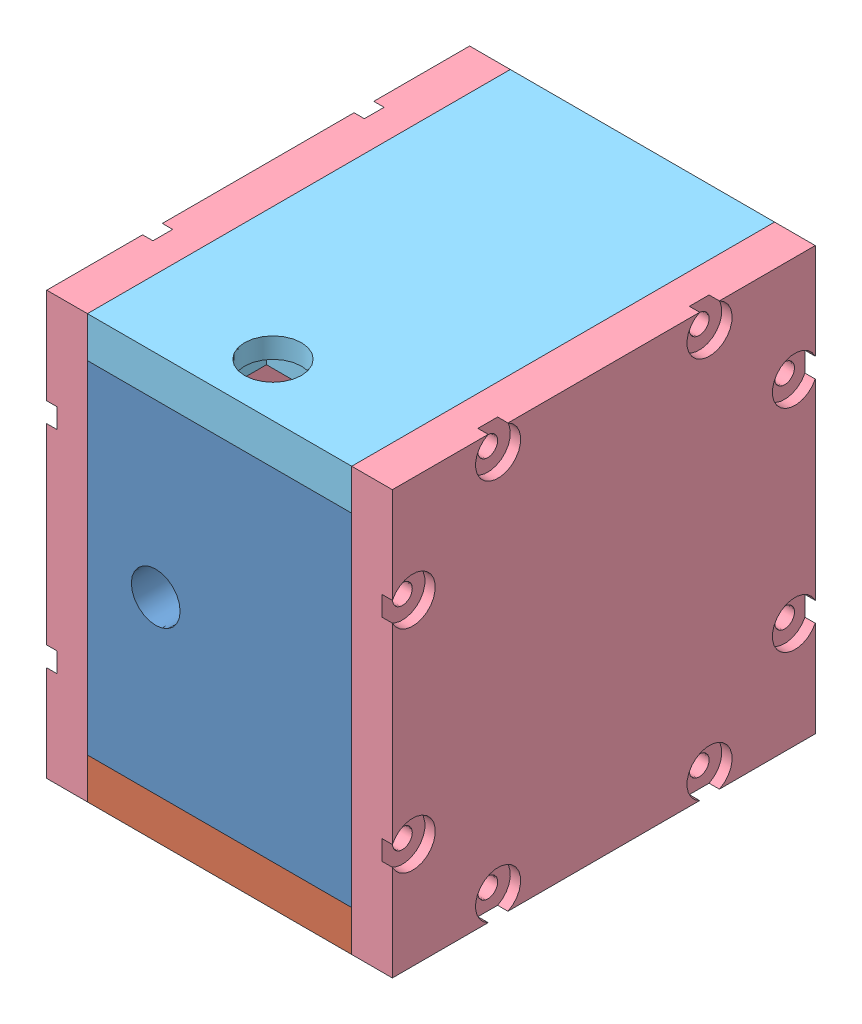
SolidWorks assembly Na_EOM_assembly, configuration Default. Lengths in mm.
Overall size (42.5 52 52).
10 component instances, 9 part files, 23 mates.
Components (placement in the parent):
- Na_EOM_back_plate-1: Na_EOM_back_plate [Default] at (-34.7103 -12.6253 57.9537) size (32.5 42 5)
- Na_EOM_bottom_plate-1: Na_EOM_bottom_plate [Default] at (-34.7103 -17.6253 62.9537) size (32.5 5 52)
- Na_EOM_front_plate-1: Na_EOM_front_plate [Default] at (-34.7103 -12.6253 10.9537) size (32.5 42 5)
- Na_EOM_side_plate-1: Na_EOM_side_plate [Default] at (-2.2103 -17.6253 62.9537) size (5 52 52)
- Na_EOM_top_plate-1: Na_EOM_top_plate [Default] at (-34.7103 29.3747 62.9537) size (32.5 5 52)
- Na_EOM_side_plate-2: Na_EOM_side_plate [Default] at (-34.7103 -17.6253 10.9537) x (-1 0 0) z (0 0 -1) size (5 52 52)
- Na_EOM_plexiglass_bottom-1: Na_EOM_plexiglass_bottom [Default] at (-27.7103 -12.6253 28.9737) x (0 0 1) z (-1 0 0) size (25.41 12 18.5)
- Na_EOM_cavity_lower-1: Na_EOM_cavity_lower [Default] at (-27.7103 -0.6253 54.3837) size (18.5 9 25.41)
- Na_EOM_cavity_upper-1: Na_EOM_cavity_upper [Default] at (-27.7103 17.3747 28.9737) x (1 0 0) z (0 0 -1) size (18.5 9 25.41)
- Na_EOM_crystal-1: Na_EOM_crystal [Default] at (-27.7103 6.8747 28.9737) size (3 3 25.41)
Mates (geometry in assembly coordinates):
- Coincident3: coincident aligned: plane of Na_EOM_bottom_plate-1 through (-34.7103 -12.6253 62.9537) normal (0 0 1); plane of Na_EOM_side_plate-1 through (2.7897 -17.6253 62.9537) normal (0 0 1)
- Coincident5: coincident anti-aligned: plane of Na_EOM_bottom_plate-1 through (-2.2103 -12.6253 62.9537) normal (1 0 0); plane of Na_EOM_side_plate-1 through (-2.2103 -17.6253 62.9537) normal (-1 0 0)
- Coincident6: coincident aligned: plane of Na_EOM_bottom_plate-1 through (-34.7103 -17.6253 62.9537) normal (0 -1 0); plane of Na_EOM_side_plate-1 through (2.7897 -17.6253 62.9537) normal (0 -1 0)
- Coincident7: coincident aligned: plane of Na_EOM_side_plate-1 through (2.7897 34.3747 62.9537) normal (0 1 0); plane of Na_EOM_top_plate-1 through (-34.7103 34.3747 62.9537) normal (0 1 0)
- Coincident9: coincident aligned: plane of Na_EOM_side_plate-1 through (2.7897 -17.6253 62.9537) normal (0 0 1); plane of Na_EOM_top_plate-1 through (-34.7103 34.3747 62.9537) normal (0 0 1)
- Coincident10: coincident anti-aligned: plane of Na_EOM_side_plate-1 through (-2.2103 -17.6253 62.9537) normal (-1 0 0); plane of Na_EOM_top_plate-1 through (-2.2103 34.3747 62.9537) normal (1 0 0)
- Coincident14: coincident aligned: plane of Na_EOM_bottom_plate-1 through (-34.7103 -12.6253 10.9537) normal (0 0 -1); plane of Na_EOM_front_plate-1 through (-34.7103 -12.6253 10.9537) normal (0 0 -1)
- Coincident15: coincident anti-aligned: plane of Na_EOM_front_plate-1 through (-2.2103 -12.6253 15.9537) normal (1 0 0); plane of Na_EOM_side_plate-1 through (-2.2103 -17.6253 62.9537) normal (-1 0 0)
- Coincident16: coincident anti-aligned: plane of Na_EOM_front_plate-1 through (-34.7103 29.3747 15.9537) normal (0 1 0); plane of Na_EOM_top_plate-1 through (-34.7103 29.3747 62.9537) normal (0 -1 0)
- Coincident17: coincident aligned: plane of Na_EOM_back_plate-1 through (-34.7103 -12.6253 62.9537) normal (0 0 1); plane of Na_EOM_side_plate-1 through (2.7897 -17.6253 62.9537) normal (0 0 1)
- Coincident18: coincident anti-aligned: plane of Na_EOM_back_plate-1 through (-34.7103 -12.6253 62.9537) normal (0 -1 0); plane of Na_EOM_bottom_plate-1 through (-34.7103 -12.6253 62.9537) normal (0 1 0)
- Coincident20: coincident aligned: plane of Na_EOM_back_plate-1 through (-34.7103 -12.6253 62.9537) normal (-1 0 0); plane of Na_EOM_top_plate-1 through (-34.7103 34.3747 62.9537) normal (-1 0 0)
- Coincident44: coincident aligned: line of Na_EOM_plexiglass_bottom-1 through (-9.2103 -12.6253 54.3837) axis (0 0 -1)
- Coincident45: coincident anti-aligned: line of Na_EOM_plexiglass_bottom-1 through (-9.2103 -12.6253 28.9737) axis (-1 0 0)
- Coincident46: coincident aligned: line of Na_EOM_plexiglass_bottom-1 through (-27.7103 -0.6253 28.9737) axis (0 0 1); line of Na_EOM_cavity_lower-1 through (-27.7103 -0.6253 28.9737) axis (0 0 1)
- Coincident47: coincident aligned: line of Na_EOM_plexiglass_bottom-1 through (-9.2103 -0.6253 28.9737) axis (-1 0 0); line of Na_EOM_cavity_lower-1 through (-9.2103 -0.6253 28.9737) axis (-1 0 0)
- Coincident55: coincident anti-aligned: line of Na_EOM_cavity_lower-1 through (-9.2103 8.3747 54.3837) axis (0 0 -1); line of Na_EOM_cavity_upper-1 through (-9.2103 8.3747 28.9737) axis (0 0 1)
- Coincident56: coincident anti-aligned: line of Na_EOM_cavity_lower-1 through (-9.2103 8.3747 28.9737) axis (-1 0 0); line of Na_EOM_cavity_upper-1 through (-12.1103 8.3747 28.9737) axis (1 0 0)
- Coincident57: coincident aligned: line of Na_EOM_cavity_upper-1 through (-27.7103 9.8747 54.3837) axis (0 0 -1); line of Na_EOM_crystal-1 through (-27.7103 9.8747 54.3837) axis (0 0 -1)
- Coincident58: coincident anti-aligned: line of Na_EOM_cavity_lower-1 through (-24.6305 6.8747 28.9737) axis (-1 0 0); line of Na_EOM_crystal-1 through (-27.7103 6.8747 28.9737) axis (1 0 0)
- Coincident59: coincident anti-aligned: line of Na_EOM_top_plate-1 through (-34.7103 34.3747 10.9537) axis (0 0 1); line of Na_EOM_side_plate-2 through (-34.7103 34.3747 62.9537) axis (0 0 -1)
- Parallel1: parallel aligned: line of Na_EOM_top_plate-1 through (-34.7103 34.3747 10.9537) axis (0 -1 0); line of Na_EOM_side_plate-2 through (-39.7103 34.3747 10.9537) axis (0 -1 0)
- Coincident61: coincident anti-aligned: line of Na_EOM_back_plate-1 through (-34.7103 29.3747 62.9537) axis (0 -1 0); line of Na_EOM_side_plate-2 through (-34.7103 -17.6253 62.9537) axis (0 1 0)
